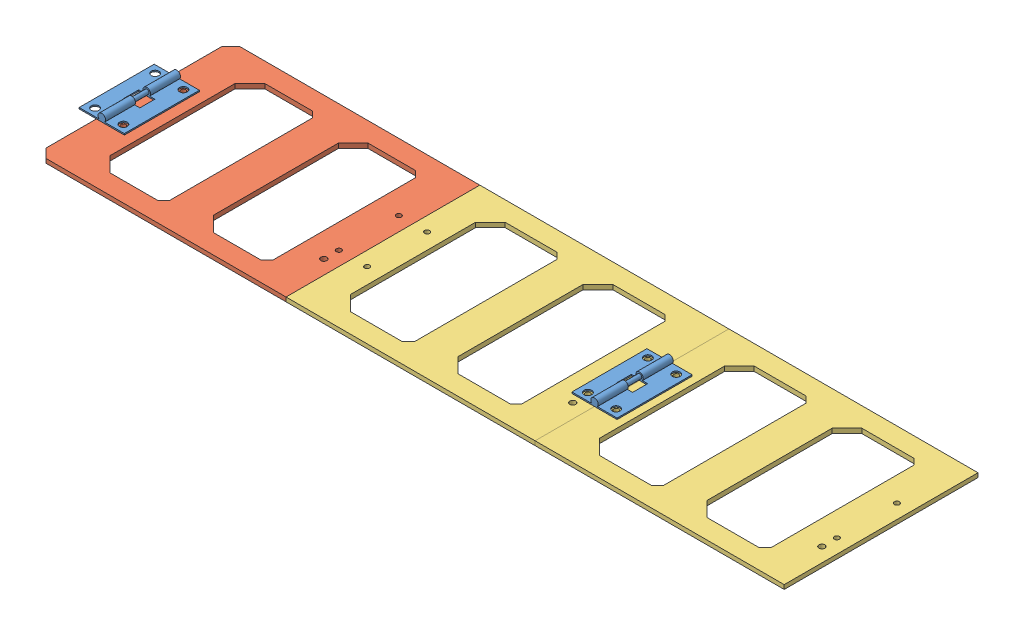
SolidWorks assembly COTS_OPEN, configuration Default. Lengths in mm.
Overall size (323.47 8.13 82).
6 component instances, 3 part files, 15 mates.
Components (placement in the parent):
- COTS_STS1114_180-1: COTS_STS1114_180 [Default] at (-5.3531 13.9448 13.2324) size (19.13 3.17 31.75)
- SP_Imperial_COTS_Hinge_BASE-1: SP_Imperial_COTS_Hinge_BASE [Default] at (54.6417 13.9448 29.1074) x (-1 0 0) z (0 -1 0) size (105.41 82 1.98)
- COTS_STS1114_180-2: COTS_STS1114_180 [Default] at (116.8971 12.1668 13.2324) x (-1 0 0) z (0 0 1) size (19.13 3.17 31.75)
- Solar_Panel_FULL_Imperial_COTS_Hinge-1: Solar_Panel_FULL_Imperial_COTS_Hinge [Default] at (160.0263 13.9448 29.1074) x (-1 0 0) z (0 -1 0) size (105.41 82 1.98)
- COTS_STS1114_180-3: COTS_STS1114_180 [Default] at (203.1555 13.9448 13.2324) size (19.13 3.17 31.75)
- Solar_Panel_FULL_Imperial_COTS_Hinge-2: Solar_Panel_FULL_Imperial_COTS_Hinge [Default] at (265.4109 13.9448 29.1074) x (-1 0 0) z (0 -1 0) size (105.41 82 1.98)
Mates (geometry in assembly coordinates):
- Coincident1: coincident anti-aligned: plane of COTS_STS1114_180-1 through (-5.3531 13.9448 44.9824) normal (0 -1 0); plane of SP_Imperial_COTS_Hinge_BASE-1 through (54.6417 13.9448 29.1074) normal (0 1 0)
- Concentric1: concentric anti-aligned: circle of COTS_STS1114_180-1; cylinder of SP_Imperial_COTS_Hinge_BASE-1 through (10.1917 12.1668 41.8074) axis (0 1 0) radius 1.0795
- Parallel1: parallel aligned: line of COTS_STS1114_180-1 through (-5.3531 14.5036 44.9824) axis (0 0 -1); line of SP_Imperial_COTS_Hinge_BASE-1 through (1.9367 13.9448 66.2974) axis (0 0 -1)
- Coincident3: coincident anti-aligned: plane of SP_Imperial_COTS_Hinge_BASE-1 through (54.6417 12.1668 29.1074) normal (0 -1 0); plane of COTS_STS1114_180-2 through (116.8971 12.1668 44.9824) normal (0 1 0)
- Parallel2: parallel aligned: line of SP_Imperial_COTS_Hinge_BASE-1 through (107.3467 12.1668 70.1074) axis (0 0 -1); line of COTS_STS1114_180-2 through (97.7709 11.608 44.9824) axis (0 0 -1)
- Concentric3: concentric anti-aligned: circle of SP_Imperial_COTS_Hinge_BASE-1; circle of COTS_STS1114_180-2
- Coincident5: coincident anti-aligned: plane of COTS_STS1114_180-2 through (116.8971 12.1668 44.9824) normal (0 1 0); plane of Solar_Panel_FULL_Imperial_COTS_Hinge-1 through (160.0263 12.1668 29.1074) normal (0 -1 0)
- Concentric4: concentric anti-aligned: circle of COTS_STS1114_180-2; circle of Solar_Panel_FULL_Imperial_COTS_Hinge-1
- Parallel3: parallel aligned: line of COTS_STS1114_180-2 through (116.8971 11.608 44.9824) axis (0 0 -1); line of Solar_Panel_FULL_Imperial_COTS_Hinge-1 through (107.3213 12.1668 70.1074) axis (0 0 -1)
- Coincident7: coincident anti-aligned: plane of Solar_Panel_FULL_Imperial_COTS_Hinge-1 through (160.0263 13.9448 29.1074) normal (0 1 0); plane of COTS_STS1114_180-3 through (203.1555 13.9448 44.9824) normal (0 -1 0)
- Concentric5: concentric anti-aligned: cylinder of Solar_Panel_FULL_Imperial_COTS_Hinge-1 through (206.7369 12.1668 16.4074) axis (0 1 0) radius 1.0795; circle of COTS_STS1114_180-3
- Parallel4: parallel aligned: line of Solar_Panel_FULL_Imperial_COTS_Hinge-1 through (212.7313 13.9448 70.1074) axis (0 0 -1); line of COTS_STS1114_180-3 through (203.1555 14.5036 44.9824) axis (0 0 -1)
- Coincident9: coincident anti-aligned: plane of COTS_STS1114_180-3 through (203.1555 13.9448 44.9824) normal (0 -1 0); plane of Solar_Panel_FULL_Imperial_COTS_Hinge-2 through (265.4109 13.9448 29.1074) normal (0 1 0)
- Concentric6: concentric anti-aligned: circle of COTS_STS1114_180-3; cylinder of Solar_Panel_FULL_Imperial_COTS_Hinge-2 through (218.7003 12.1668 16.4074) axis (0 1 0) radius 1.0795
- Parallel5: parallel aligned: line of COTS_STS1114_180-3 through (222.2817 13.9448 44.9824) axis (0 0 -1); line of Solar_Panel_FULL_Imperial_COTS_Hinge-2 through (212.7059 12.1668 70.1074) axis (0 0 -1)
